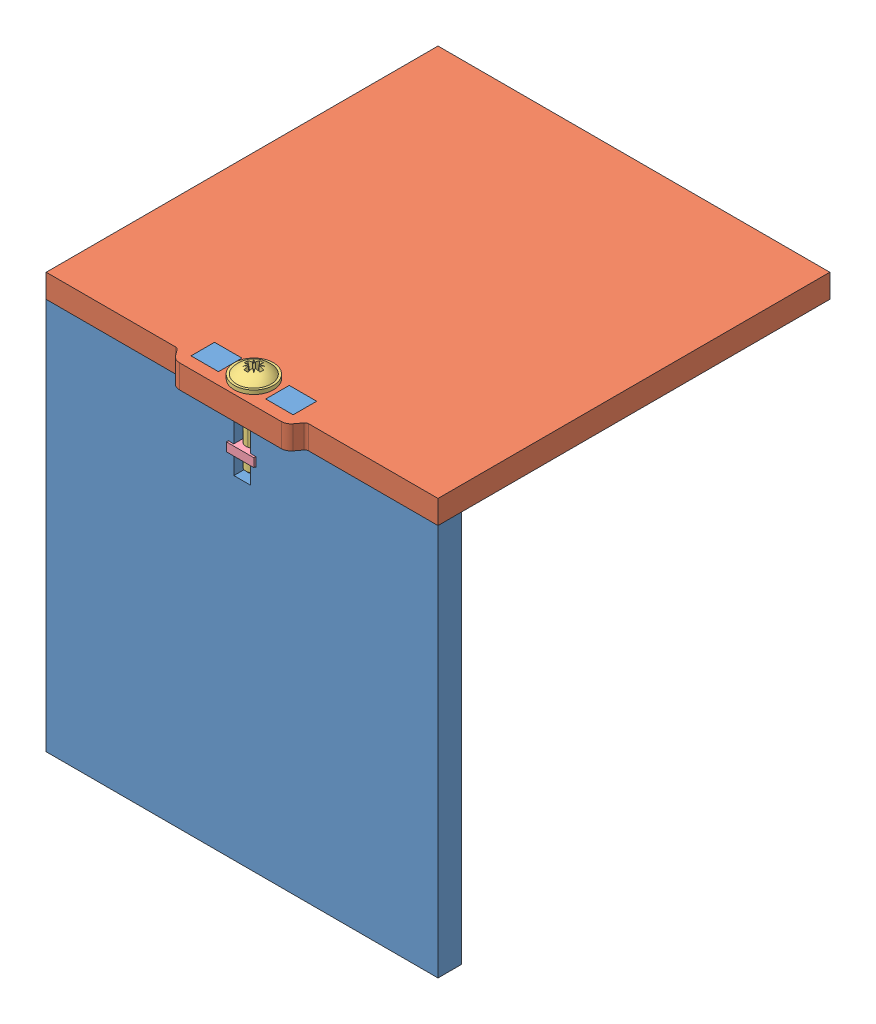
SolidWorks assembly auto_mount, configuration По умолчанию. Lengths in mm.
Overall size (100 108.96 113.56).
4 component instances, 4 part files, 9 mates.
Components (placement in the parent):
- plywood_test-1: plywood_test [По умолчанию] at (51.7183 54.318 64.1682) size (100 106 6)
- plywood_test2-2: plywood_test2 [По умолчанию] at (51.7183 104.318 20.1682) x (-1 0 0) z (0 1 0) size (100 103 6)
- DIN967_2-1: DIN967_2 [M4х20] at (51.7183 113.368 67.1682) x (0 -1 0) z (0 0 1) size (22.96 34 34.42)
- din 562 m4-1: din 562 m4 [По умолчанию] at (51.7181 96.318 67.1664) x (1 0 0) z (0 -1 0) size (7 7 2.2)
Mates (geometry in assembly coordinates):
- Совпадение1: coincident aligned: plane of plywood_test-1 through (51.7183 54.318 70.1682) normal (0 0 1); plane of plywood_test2-2 through (101.7183 110.318 70.1682) normal (0 0 1)
- Совпадение2: coincident anti-aligned: plane of plywood_test-1 through (1.7183 104.318 70.1682) normal (0 1 0); plane of plywood_test2-2 through (51.7183 104.318 20.1682) normal (0 -1 0)
- Совпадение3: coincident aligned: plane of plywood_test-1 through (101.7183 4.318 70.1682) normal (1 0 0); plane of plywood_test2-2 through (101.7183 110.318 -29.8318) normal (1 0 0)
- Совпадение5: coincident anti-aligned: plane of plywood_test2-2 through (51.7183 110.318 20.1682) normal (0 1 0); plane of DIN967-1 through (53.7183 110.318 67.1682) normal (0 -1 0)
- Совпадение6: coincident: plane of plywood_test-1 through (51.7183 54.318 67.1682) normal (0 0 1); line of DIN967-1 through (51.7183 119.2763 67.1682) axis (0 -1 0)
- Совпадение7: coincident: line of DIN967-1 through (51.7183 119.2763 67.1682) axis (0 -1 0)
- Концентричный1: concentric anti-aligned: cylinder of DIN967-1 through (51.7183 119.718 67.1682) axis (0 1 0) radius 2; cylinder of din 562 m4-1 through (51.7183 96.318 67.1682) axis (0 -1 0) radius 2
- Совпадение8: coincident anti-aligned: plane of plywood_test-1 through (49.6183 96.318 64.1682) normal (0 -1 0); plane of din 562 m4-1 through (51.7181 96.318 67.1664) normal (0 1 0)
- Совпадение9: coincident anti-aligned: plane of plywood_test-1 through (51.7183 54.318 70.1682) normal (0 0 1); plane of DIN967-1 through (51.7183 113.368 70.1682) normal (0 0 -1)
